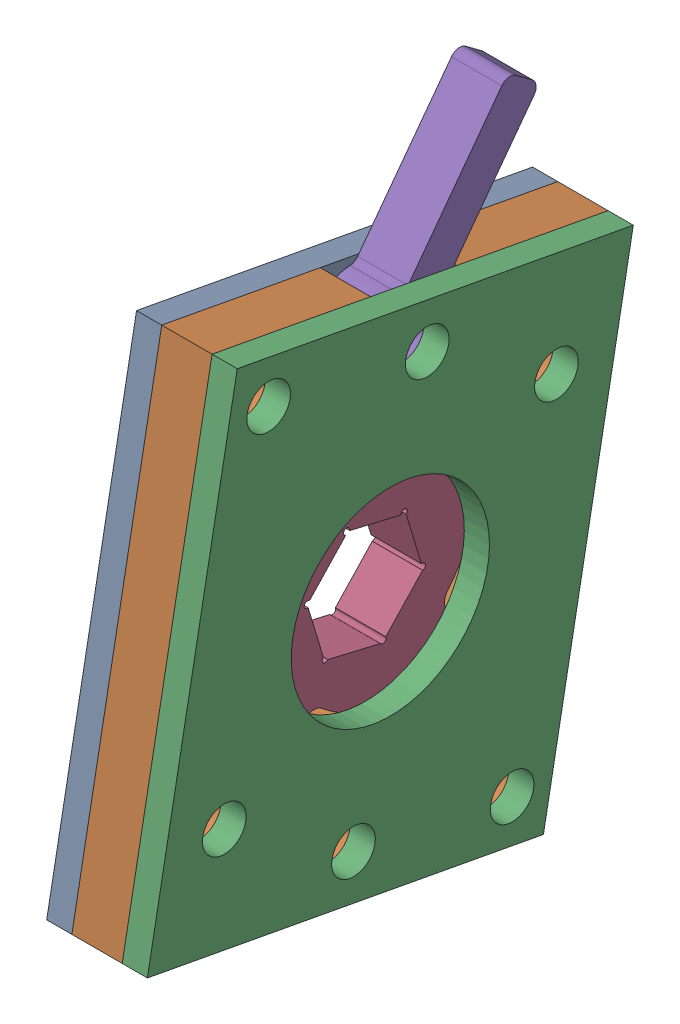
SolidWorks assembly max planetary ratchet, configuration Default. Lengths in mm.
Overall size (12.7 83.56 61.27).
6 component instances, 6 part files, 14 mates.
Components (placement in the parent):
- housing1-1: housing1 [Default] at (674.6713 854.4828 1326.8729) x (1 0 0) z (0 0.183005 0.983112) size (3.17 61.92 50.8)
- housing2-1: housing2 [Default] at (677.8463 854.4828 1326.8729) x (1 0 0) z (0 0.183005 0.983112) size (6.35 61.92 50.8)
- housing3-1: housing3 [Default] at (684.1963 854.4828 1326.8729) x (1 0 0) z (0 0.183005 0.983112) size (3.17 61.92 50.8)
- ratchet-1: ratchet [Default] at (677.8463 880.2723 1296.2359) x (0 0.685261 0.728297) z (1 0 0) size (30.96 30.96 6.35)
- pawl-1: pawl [Default] at (677.8463 946.6064 1294.3481) x (0 -0.802065 0.597237) z (1 0 0) size (36.12 17.17 6.35)
- am-4424 Ratchet Sport.STEP-1: am-4424 Ratchet Sport.STEP [Default] at (670.8572 931.2581 1444.7631) x (0 0 1) z (-1 0 0) (suppressed, hidden)
Mates (geometry in assembly coordinates):
- Coincident2: coincident anti-aligned: plane of housing2-1 through (684.1963 854.4828 1326.8729) normal (1 0 0); plane of housing3-1 through (684.1963 854.4828 1326.8729) normal (-1 0 0)
- Coincident4: coincident aligned: plane of housing2-1 through (684.1963 854.4828 1326.8729) normal (0 0.183005 0.983112); plane of housing3-1 through (687.3713 854.4828 1326.8729) normal (0 0.183005 0.983112)
- Coincident6: coincident aligned: plane of housing2-1 through (684.1963 915.3571 1315.5412) normal (0 0.983112 -0.183005); plane of housing3-1 through (687.3713 915.3571 1315.5412) normal (0 0.983112 -0.183005)
- Coincident10: coincident anti-aligned: plane of housing3-1 through (684.1963 854.4828 1326.8729) normal (-1 0 0); plane of ratchet-1 through (684.1963 880.2723 1296.2359) normal (1 0 0)
- Concentric1: concentric: cylinder of housing2-1 through (684.1963 880.2723 1296.2359) axis (-1 0 0) radius 16; point of ratchet-1
- Coincident14: coincident anti-aligned: plane of housing1-1 through (677.8463 854.4828 1326.8729) normal (1 0 0); plane of pawl-1 through (677.8463 946.6064 1294.3481) normal (-1 0 0)
- Coincident16: coincident anti-aligned: plane of housing1-1 through (677.8463 854.4828 1326.8729) normal (1 0 0); plane of ratchet-1 through (677.8463 880.2723 1296.2359) normal (-1 0 0)
- Coincident19: coincident anti-aligned: line of ratchet-1 through (684.1963 870.9372 1284.1633) axis (0 0.685261 0.728297); line of am-4424 Ratchet Sport.STEP-1 through (681.5483 895.3135 1300.9751) axis (0 1 0)
- Coincident20: coincident anti-aligned: line of ratchet-1 through (684.1963 892.1703 1287.0559) axis (0 -0.728297 0.685261); line of am-4424 Ratchet Sport.STEP-1 through (681.5483 880.7822 1312.3314) axis (0 0 1)
- Parallel4: parallel aligned: plane of housing2-1 through (684.1963 854.4828 1326.8729) normal (0 0.183005 0.983112); plane of am-4424 Ratchet Sport.STEP-1 through (688.9623 882.3697 1323.2001) normal (0 0 1)
- Coincident21: coincident anti-aligned: plane of housing1-1 through (677.8463 854.4828 1326.8729) normal (1 0 0); plane of housing2-1 through (677.8463 854.4828 1326.8729) normal (-1 0 0)
- Coincident22: coincident aligned: plane of housing1-1 through (677.8463 854.4828 1326.8729) normal (0 0.183005 0.983112); plane of housing2-1 through (684.1963 854.4828 1326.8729) normal (0 0.183005 0.983112)
- Coincident23: coincident aligned: plane of housing1-1 through (677.8463 915.3571 1315.5412) normal (0 0.983112 -0.183005); plane of housing2-1 through (684.1963 915.3571 1315.5412) normal (0 0.983112 -0.183005)
- Concentric4: concentric aligned: cylinder of housing3-1 through (687.3713 905.2427 1291.588) axis (-1 0 0) radius 2.75; cylinder of pawl-1 through (684.1963 905.2427 1291.588) axis (-1 0 0) radius 2.75
